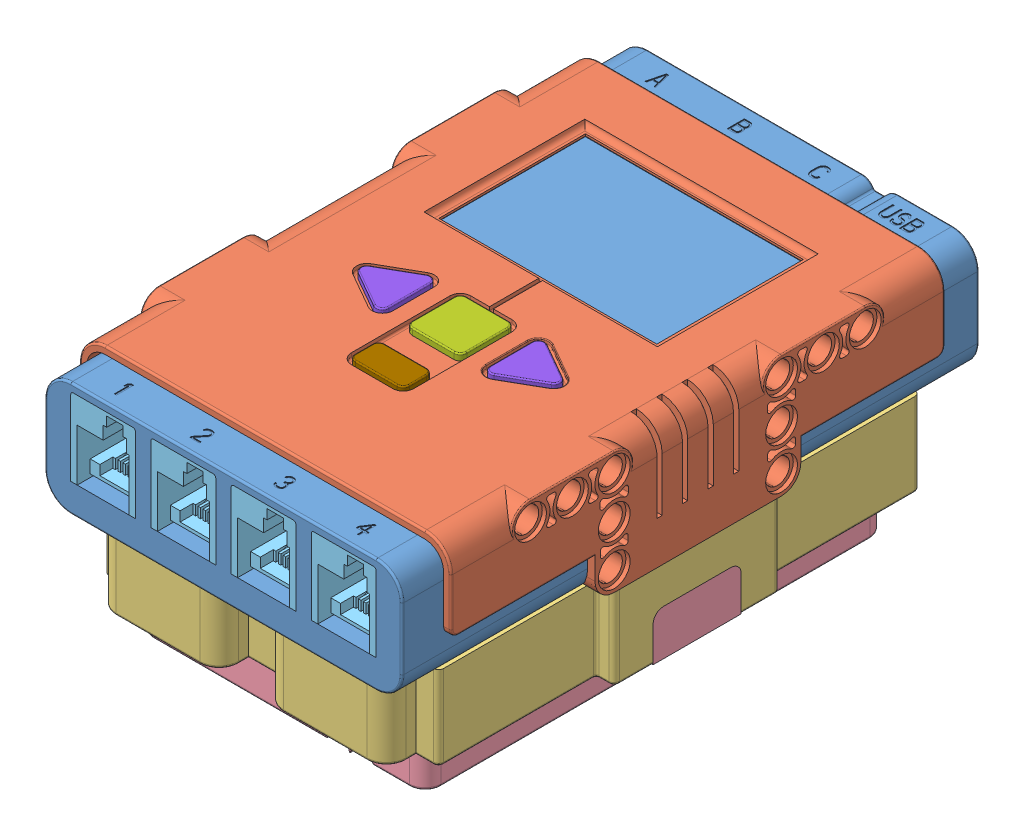
SolidWorks assembly NXT, configuration Default. Lengths in mm.
Overall size (71.61 47.78 111.26).
16 component instances, 9 part files, 0 mates.
Components (placement in the parent):
- NXT Interior-1: NXT Interior [Default] at origin size (68.88 22 111.26)
- NXT Shell-1: NXT Shell [Default] at (0.0375 -0.17 0) size (71.61 23.57 95.25)
- NXT Battery Case-1: NXT Battery Case [Default] x (1 0 0) z (0 0 -1) size (71.38 16.13 104.22)
- NXT Battery-1: NXT Battery [Default] at (0 -14.125 0) x (-1 0 0) z (0 0 1) size (69.68 23.25 89.34)
- NXT Socket-1: NXT Socket [Default] at (-23.1925 13 55.625) x (1 0 0) z (0 0 -1) size (12.5 15 12.59)
- NXT Socket-2: NXT Socket [Default] at (-7.7325 13 55.625) x (1 0 0) z (0 0 -1) size (12.5 15 12.59)
- NXT Socket-3: NXT Socket [Default] at (7.7275 13 55.625) x (1 0 0) z (0 0 -1) size (12.5 15 12.59)
- NXT Socket-4: NXT Socket [Default] at (23.1875 13 55.625) x (1 0 0) z (0 0 -1) size (12.5 15 12.59)
- NXT Socket-5: NXT Socket [Default] at (-23.1925 13 -55.625) x (-1 0 0) z (0 0 1) size (12.5 15 12.59)
- NXT Socket-6: NXT Socket [Default] at (-7.7325 13 -55.625) x (-1 0 0) z (0 0 1) size (12.5 15 12.59)
- NXT Socket-7: NXT Socket [Default] at (7.7275 13 -55.625) x (-1 0 0) z (0 0 1) size (12.5 15 12.59)
- NXT Socket USB-1: NXT Socket USB [Default] at (23.1875 10.75 -43.125) x (-1 0 0) z (0 0 -1) size (12.5 10.5 12.5)
- NXT Button 1-1: NXT Button 1 [Default] at (0.0375 22 10) size (10.5 1.65 10.5)
- NXT Button 2-1: NXT Button 2 [Default] at (-14.4625 22 10) size (9.5 1.65 10.5)
- NXT Button 2-2: NXT Button 2 [Default] at (14.5375 22 10) x (-1 0 0) z (0 0 -1) size (9.5 1.65 10.5)
- NXT Button 3-1: NXT Button 3 [Default] at (0.0375 22 23.375) size (10.5 1.65 5.75)
